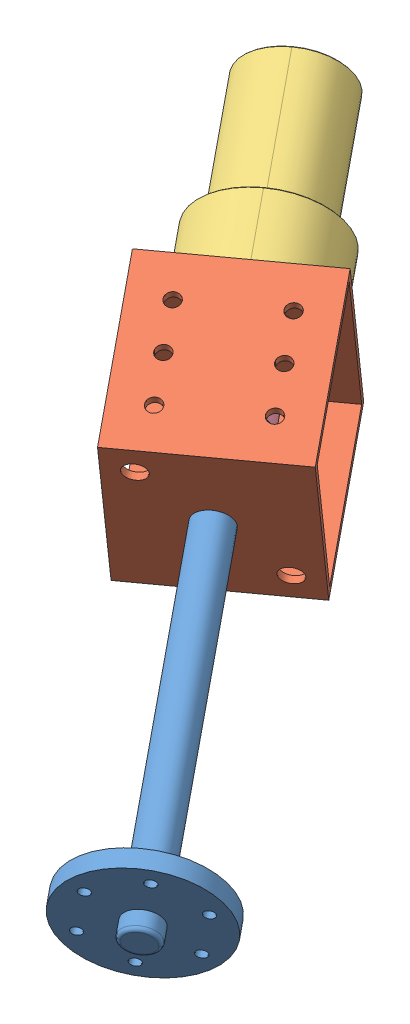
SolidWorks assembly link 3  assembly.STEP, configuration Default. Lengths in mm.
Overall size (171.91 113.92 202.66).
5 component instances, 4 part files, 0 mates.
Components (placement in the parent):
- link2_v4.STEP-1-1: link2_v4.STEP-1 [Default] at (-235.8163 1361.7477 -204.2515) x (-0.578814 -0.044282 0.814256) z (-0.794667 0.254678 -0.551038) size (77.07 57.23 126.21)
  - NEW_4th motor shaft.STEP-1-1: NEW_4th motor shaft.STEP-1 [Default] at (31.3806 -275.6354 -349.6555) x (0.946363 0.122416 0.299019) z (-0.312536 0.112037 0.943276) size (40 40 115)
- motor4 hub.STEP-1-1: motor4 hub.STEP-1 [Default] at (-75.7841 1049.6045 -142.3089) x (0.54819 -0.362301 0.753807) z (-0.808753 0 0.588148) size (49 49 45)
- v2johnson pivot dc motor 10rpm.STEP-1-1: v2johnson pivot dc motor 10rpm.STEP-1 [Default] at (-108.9033 1051.9565 -149.595) x (0.808753 0 -0.588148) z (0.213087 0.932061 0.293012) size (37 101.3 37)
- Coupler 6.35-8mm.STEP-1-1: Coupler 6.35-8mm.STEP-1 [Default] at (-91.4641 1047.941 -125.6145) x (-0.5007 -0.864106 -0.05119) z (-0.54819 0.362301 -0.753807) size (19.33 19.33 25)
